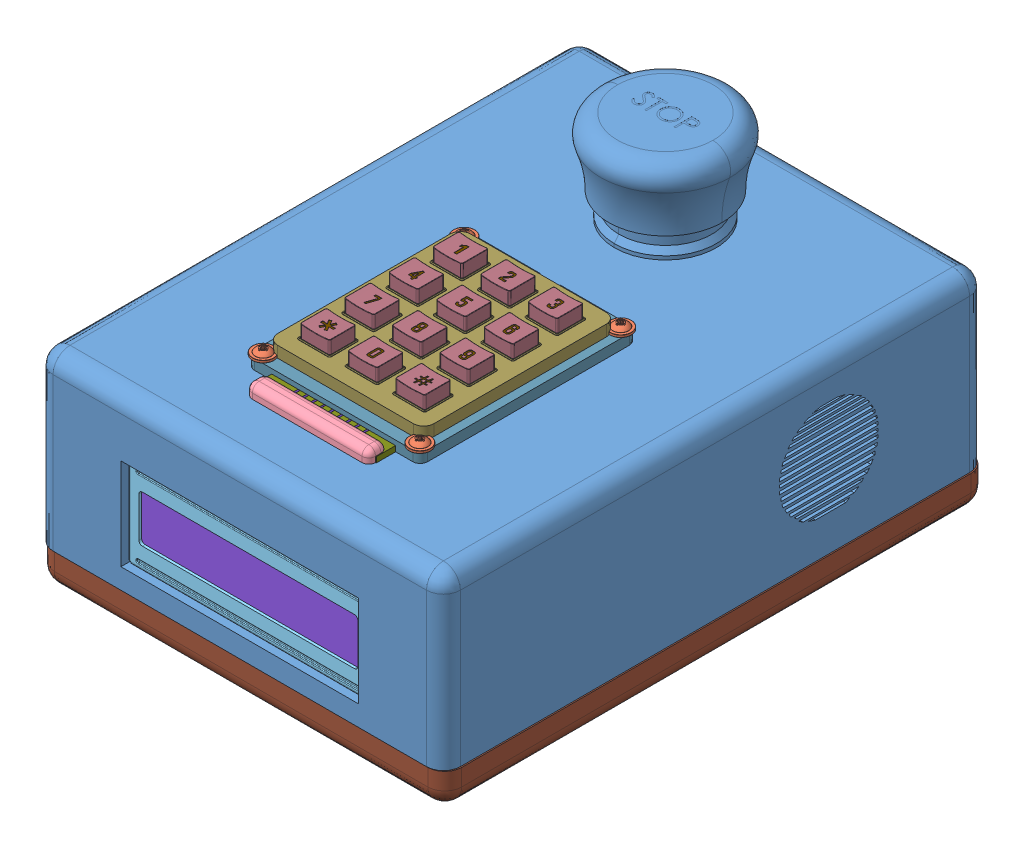
SolidWorks assembly body assem, configuration Default. Lengths in mm.
Overall size (120.39 92.06 160).
42 component instances, 22 part files, 5 mates.
Components (placement in the parent):
- body-1: body [Default] at (15.3376 122.7226 24.9096) size (120 50 160)
- pin1 lcd-1: pin1 lcd [Default] at (113.4876 109.1226 170.0096) size (3 3 5)
- pin1 lcd-2: pin1 lcd [Default] at (113.4876 78.1226 170.0096) size (3 3 5)
- pin1 lcd-3: pin1 lcd [Default] at (38.4876 78.1226 170.0096) size (3 3 5)
- pin1 lcd-4: pin1 lcd [Default] at (38.4876 109.1226 170.0096) size (3 3 5)
- LCD-2: LCD [Default] at (75.9876 93.6226 173.2096) x (1 0 0) z (0 -1 0) size (80 18.3 36)
  - pcbboard-1: pcbboard [Default] at origin size (80 4.2 36)
  - 16pin_header__-1: 16pin_header__ [Default] at (-32 0 -15.5) x (0 0 1) z (1 0 0) size (2.54 11.5 40.64)
  - lcd window-1: lcd window [Default] at (0 9 1.5) size (71.3 11.8 27.44)
  - backlight-1: backlight [Default] at (0 1.7 1.5) x (-1 0 0) z (0 0 -1) size (74.38 2.98 18)
  - conductor-1: conductor [Default] at (0 1.7 12.6) size (69.7 5.5 3)
  - conductor-2: conductor [Default] at (0 1.7 -9.6) size (69.7 5.5 3)
  - liquid crystal grabcad-1: liquid crystal grabcad [Default] at (0 7.9 1.5) size (68.5 2.2 25)
  - smt_resistor222-1: smt_resistor222 [Default] at (-32.75 0 -5.25) x (0 0 1) z (1 0 0) size (1.8 0.6 4)
  - smt_resistor222-2: smt_resistor222 [Default] at (-32.75 0 -2.75) x (0 0 1) z (1 0 0) size (1.8 0.6 4)
  - smt_resistor222-3: smt_resistor222 [Default] at (-32.75 0 -0.25) x (0 0 1) z (1 0 0) size (1.8 0.6 4)
  - smt_resistor222-4: smt_resistor222 [Default] at (-32.75 0 2.25) x (0 0 1) z (1 0 0) size (1.8 0.6 4)
  - smt_resistor222-5: smt_resistor222 [Default] at (-32.75 0 4.75) x (0 0 1) z (1 0 0) size (1.8 0.6 4)
  - smt_resistor222-6: smt_resistor222 [Default] at (-32.75 0 7.25) x (0 0 1) z (1 0 0) size (1.8 0.6 4)
  - smt_resistor101-1: smt_resistor101 [Default] at (30.25 0 6.1) x (0 0 -1) z (-1 0 0) size (1.8 0.6 5.2)
  - smt_resistor101-2: smt_resistor101 [Default] at (30.25 0 2.85) x (0 0 -1) z (-1 0 0) size (1.8 0.6 5.2)
- ini-1: ini [Default] at (-14.6305 164.5173 32.943) x (1 0 0) z (0 -1 0) size (120 160 92.06)
  - base-1: base [Default] at (30.3532 151.9666 91.7947) size (120 160 10)
  - KeyPad_3x4_w_pcb-1: KeyPad_3x4_w_pcb [Default] at (91.866 94.3035 38.7947) x (1 0 0) z (0 0 -1) size (51 69.5 10.29)
    - KeyPad_3x4_w_pcb.step-1: KeyPad_3x4_w_pcb.step [Default] at origin size (51 69.5 10.29)
      - Body_top.step-1: Body_top.step [Default] at origin size (46 56.8 3.6)
      - KeyPad.step-1: KeyPad.step [Default] at origin size (44.02 53.35 7.29)
      - Body_bottom.step-1: Body_bottom.step [Default] at origin size (51 63.8 3)
      - PCB_pads.step-1: PCB_pads.step [Default] at origin size (36.4 5.6 1.61)
      - PCB.step-1: PCB.step [Default] at origin size (36.5 5.7 1.6)
      - PCBtracks.step-1: PCBtracks.step [Default] at origin size (36.45 5.65 1.6)
      - KeyPad_collor.step-1: KeyPad_collor.step [Default] at origin size (40 50 6.89)
  - Emergency Stop Button-2: Emergency Stop Button [Default] at (90.3533 26.9639 34.7353) x (0.999972 0.007536 0) z (-0.007536 0.999972 0) size (38.72 65.6 38.72)
  - STP310400160-1: STP310400160 [Default] at (68.791 64.7287 37.5551) x (1 0 0) z (0 1 0) size (6.25 12.93 6.25)
  - STP310400160-2: STP310400160 [Default] at (114.941 64.7287 37.5551) x (1 0 0) z (0 1 0) size (6.25 12.93 6.25)
  - STP310400160-3: STP310400160 [Default] at (68.791 123.8787 37.5551) x (1 0 0) z (0 1 0) size (6.25 12.93 6.25)
  - STP310400160-4: STP310400160 [Default] at (114.941 123.8787 37.5551) x (1 0 0) z (0 1 0) size (6.25 12.93 6.25)
  - leg-5: leg [Default] at (43.0816 4.9248 106.7947) x (-0.998999 -0.044741 0) z (0 0 -1) size (8 8 5)
  - leg-6: leg [Default] at (137.6443 139.0201 106.7947) x (-0.998999 -0.044741 0) z (0 0 -1) size (8 8 5)
  - leg-7: leg [Default] at (136.4751 4.5046 106.7947) x (-0.998999 -0.044741 0) z (0 0 -1) size (8 8 5)
  - leg-8: leg [Default] at (43.1186 138.1725 106.7947) x (-0.998999 -0.044741 0) z (0 0 -1) size (8 8 5)
  - cover-1: cover [Default] at (109.9211 133.9035 40.1947) x (-1 0 0) z (0 0 -1) size (36.3 5.6 3.6)
Mates (geometry in assembly coordinates):
- Coincident1: coincident: plane of body-1 through (25.3376 117.7226 174.9096) normal (0 0 -1); plane of LCD-2/pcbboard-1 through (75.9876 93.6226 174.9096) normal (0 0 1)
- Concentric2: concentric: cylinder of pin1 lcd-3 through (38.4876 78.1226 175.0096) axis (0 0 -1) radius 1.5; cylinder of LCD-2/pcbboard-1 through (38.4876 78.1226 174.9096) axis (0 0 -1) radius 1.5
- Concentric3: concentric: cylinder of pin1 lcd-2 through (113.4876 78.1226 175.0096) axis (0 0 -1) radius 1.5; cylinder of LCD-2/pcbboard-1 through (113.4876 78.1226 174.9096) axis (0 0 -1) radius 1.5
- Coincident2: coincident: plane of body-1 through (15.3376 72.7226 184.9096) normal (0 -1 0); plane of ini-1/base-1 through (15.7228 72.7226 184.9096) normal (0 1 0)
- Coincident3: coincident: line of body-1 through (20.3376 72.7226 184.9096) axis (1 0 0); line of ini-1/base-1 through (130.7228 72.7226 184.9096) axis (-1 0 0)
